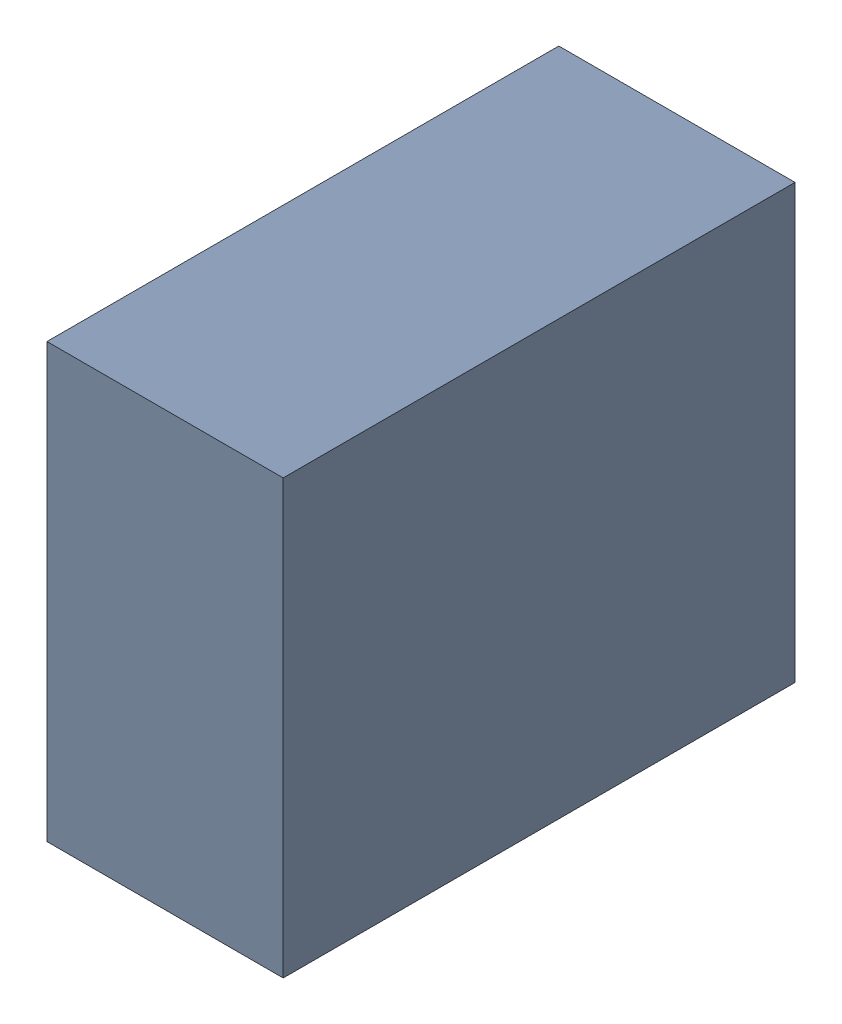
SolidWorks assembly C22_TDA1, configuration Standard. Lengths in mm.
Overall size (0.6 1.1 1.3).
2 component instances, 1 part files, 0 mates.
Components (placement in the parent):
- 885542376-1: 885542376 [Standard] at (-4.82 53.44 0) size (0.6 1.1 1.3)
  - Extruded_25-1: Extruded_25 [Standard] at origin size (0.6 1.1 1.3)
